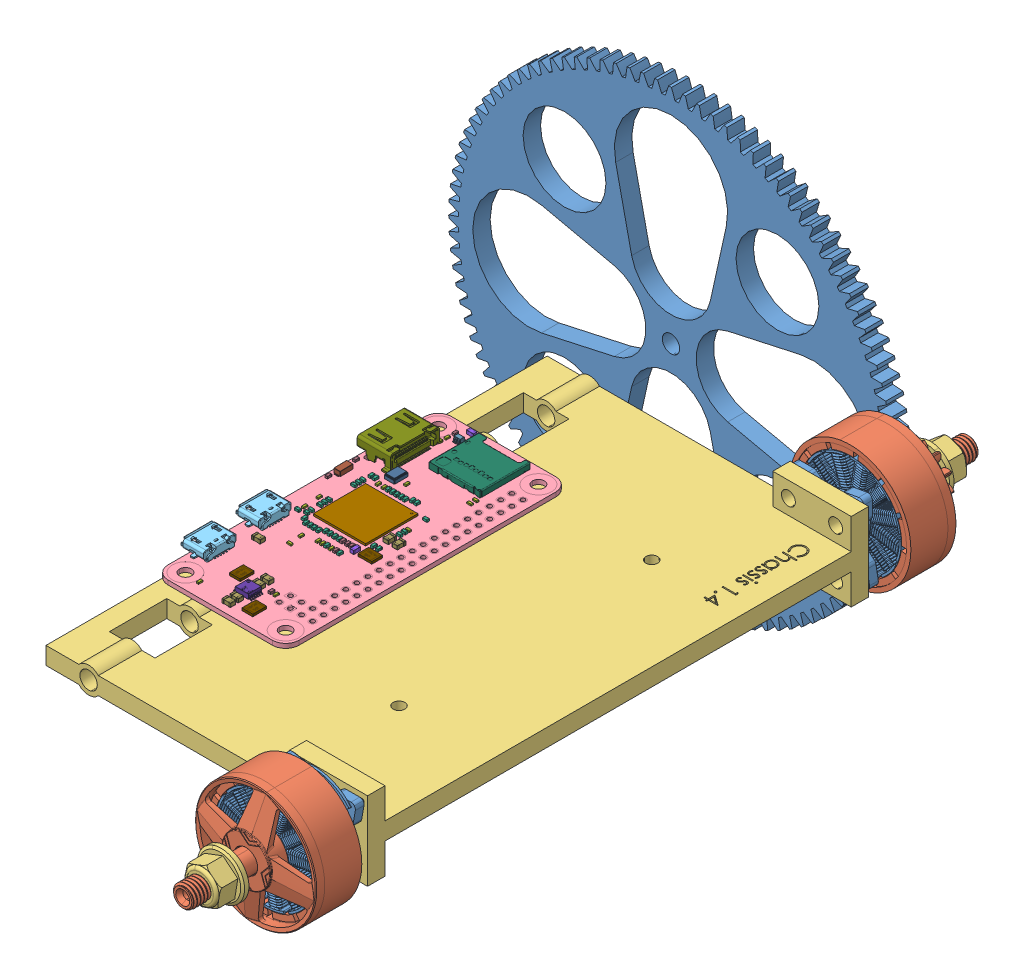
SolidWorks assembly dualwheel-drone, configuration Default. Lengths in mm.
Overall size (145.46 134.3 180.41).
93 component instances, 21 part files, 20 mates.
Components (placement in the parent):
- 100 spur gear 1 mod-1: 100 spur gear 1 mod [Metric - Spur gear 1M 100T 20PA 4FW ---S100N75H50L4N] at (0 0 -17) x (0 0 1) z (-0.401006 0.916076 0) size (4 101.97 101.97)
- spur gear_am-1: spur gear_am [Metric - Spur gear 1M 10T 20PA 4FW ---S10N75H50L5N] at (55 0 -17) x (0 0 1) z (-0.452539 -0.891745 0) size (4 11.48 12)
- chassis-full-1: chassis-full [Default] at (64 0 5.64) x (0 0 1) z (-1 0 0) size (115 18 73.78)
- RapberryPiZero.STEP-1: RapberryPiZero.STEP [Default] at (18.2777 -17.0965 114.3964) x (0 0 1) z (-1 0 0) size (65 4.45 31.23)
  - Raspberry_pizero_PCB.STEP-1: Raspberry_pizero_PCB.STEP [Default] at (-51.2564 20.0966 13.0542) size (65 1 30)
  - Micro USB_input_female (short)-SMT.STEP-1: Micro USB_input_female (short)-SMT.STEP [Default] at (-42.3564 22.3216 26.5042) size (7.98 2.94 5.43)
  - Micro USB_input_female (short)-SMT.STEP-2: Micro USB_input_female (short)-SMT.STEP [Default] at (-29.7564 22.3216 26.5042) size (7.98 2.94 5.43)
  - 0204 - Capacitor.STEP-1: 0204 - Capacitor.STEP [Default] at (-62.4121 21.3466 11.2398) size (1 0.5 0.6)
  - 0204 - Capacitor.STEP-2: 0204 - Capacitor.STEP [Default] at (-62.4121 21.3466 12.2528) size (1 0.5 0.6)
  - 0204 - Capacitor.STEP-3: 0204 - Capacitor.STEP [Default] at (-61.8122 21.3466 13.3136) size (1 0.5 0.6)
  - 0204 - Capacitor.STEP-4: 0204 - Capacitor.STEP [Default] at (-61.8122 21.3466 14.2646) size (1 0.5 0.6)
  - 0204 - Capacitor.STEP-5: 0204 - Capacitor.STEP [Default] at (-61.8122 21.3466 15.241) size (1 0.5 0.6)
  - 0204 - Capacitor.STEP-6: 0204 - Capacitor.STEP [Default] at (-61.8122 21.3466 16.2144) size (1 0.5 0.6)
  - 0204 - Capacitor.STEP-7: 0204 - Capacitor.STEP [Default] at (-61.8122 21.3466 17.2416) size (1 0.5 0.6)
  - 0204 - Capacitor.STEP-8: 0204 - Capacitor.STEP [Default] at (-62.5919 21.3466 20.9695) size (1 0.5 0.6)
  - 0204 - Capacitor.STEP-9: 0204 - Capacitor.STEP [Default] at (-62.5919 21.3466 21.919) size (1 0.5 0.6)
  - 0204 - Capacitor.STEP-10: 0204 - Capacitor.STEP [Default] at (-60.4584 21.3466 22.3712) x (0 0 1) z (-1 0 0) size (1 0.5 0.6)
  - 0204 - Capacitor.STEP-11: 0204 - Capacitor.STEP [Default] at (-60.0807 21.3466 22.3712) x (0 0 -1) z (1 0 0) size (1 0.5 0.6)
  - 0204 - Capacitor.STEP-12: 0204 - Capacitor.STEP [Default] at (-59.0466 21.3466 22.3712) x (0 0 -1) z (1 0 0) size (1 0.5 0.6)
  - 0204 - Capacitor.STEP-13: 0204 - Capacitor.STEP [Default] at (-52.6496 21.3466 22.316) x (0 0 1) z (-1 0 0) size (1 0.5 0.6)
  - 0204 - Capacitor.STEP-14: 0204 - Capacitor.STEP [Default] at (-52.25 21.3466 22.316) x (0 0 -1) z (1 0 0) size (1 0.5 0.6)
  - 0204 - Capacitor.STEP-15: 0204 - Capacitor.STEP [Default] at (-51.2398 21.3466 22.316) x (0 0 -1) z (1 0 0) size (1 0.5 0.6)
  - 0204 - Capacitor.STEP-16: 0204 - Capacitor.STEP [Default] at (-49.1841 21.3466 22.316) x (0 0 -1) z (1 0 0) size (1 0.5 0.6)
  - 0204 - Capacitor.STEP-17: 0204 - Capacitor.STEP [Default] at (-48.1448 21.3466 22.316) x (0 0 -1) z (1 0 0) size (1 0.5 0.6)
  - 0204 - Capacitor.STEP-18: 0204 - Capacitor.STEP [Default] at (-46.475 21.3466 21.113) size (1 0.5 0.6)
  - 0204 - Capacitor.STEP-19: 0204 - Capacitor.STEP [Default] at (-45.7322 21.3466 20.0663) size (1 0.5 0.6)
  - 0204 - Capacitor.STEP-20: 0204 - Capacitor.STEP [Default] at (-45.7322 21.3466 19.0675) size (1 0.5 0.6)
  - 0204 - Capacitor.STEP-21: 0204 - Capacitor.STEP [Default] at (-45.7322 21.3466 18.1249) size (1 0.5 0.6)
  - 0204 - Capacitor.STEP-22: 0204 - Capacitor.STEP [Default] at (-45.7322 21.3466 17.1095) size (1 0.5 0.6)
  - 0204 - Capacitor.STEP-23: 0204 - Capacitor.STEP [Default] at (-46.3457 21.3466 16.1412) size (1 0.5 0.6)
  - 0204 - Capacitor.STEP-24: 0204 - Capacitor.STEP [Default] at (-46.3457 21.3466 15.1229) size (1 0.5 0.6)
  - 0204 - Capacitor.STEP-25: 0204 - Capacitor.STEP [Default] at (-46.3457 21.3466 14.0197) size (1 0.5 0.6)
  - 0204 - Capacitor.STEP-26: 0204 - Capacitor.STEP [Default] at (-46.3457 21.3466 12.9589) size (1 0.5 0.6)
  - 0204 - Capacitor.STEP-27: 0204 - Capacitor.STEP [Default] at (-43.6156 21.3466 13.1418) size (1 0.5 0.6)
  - 0204 - Capacitor.STEP-28: 0204 - Capacitor.STEP [Default] at (-43.6156 21.3466 10.1424) size (1 0.5 0.6)
  - 0204 - Capacitor.STEP-29: 0204 - Capacitor.STEP [Default] at (-48.9117 21.3466 7.6917) size (1 0.5 0.6)
  - 0204 - Capacitor.STEP-30: 0204 - Capacitor.STEP [Default] at (-55.4926 21.3466 7.2526) x (0 0 -1) z (1 0 0) size (1 0.5 0.6)
  - 0204 - Capacitor.STEP-31: 0204 - Capacitor.STEP [Default] at (-53.7932 21.3466 7.2526) x (0 0 1) z (-1 0 0) size (1 0.5 0.6)
  - 0204 - Capacitor.STEP-32: 0204 - Capacitor.STEP [Default] at (-59.8477 21.3466 7.2526) x (0 0 1) z (-1 0 0) size (1 0.5 0.6)
  - 0204- Resistor.STEP-1: 0204- Resistor.STEP [Default] at (-43.6109 21.4522 15.4193) x (-1 0 0) z (0 -1 0) size (0.99 0.51 0.36)
  - 0204- Resistor.STEP-2: 0204- Resistor.STEP [Default] at (-43.6109 21.4522 14.4127) x (-1 0 0) z (0 -1 0) size (0.99 0.51 0.36)
  - 0204- Resistor.STEP-3: 0204- Resistor.STEP [Default] at (-43.6109 21.4522 12.4047) x (-1 0 0) z (0 -1 0) size (0.99 0.51 0.36)
  - 0204- Resistor.STEP-4: 0204- Resistor.STEP [Default] at (-42.6936 21.4522 18.4076) x (-1 0 0) z (0 -1 0) size (0.99 0.51 0.36)
  - 0204- Resistor.STEP-5: 0204- Resistor.STEP [Default] at (-39.831 21.4522 18.1462) x (0 0 1) z (0 -1 0) size (0.99 0.51 0.36)
  - 0204- Resistor.STEP-6: 0204- Resistor.STEP [Default] at (-61.8169 21.4522 19.8533) x (-1 0 0) z (0 -1 0) size (0.99 0.51 0.36)
  - 0204- Resistor.STEP-7: 0204- Resistor.STEP [Default] at (-61.8169 21.4522 18.5178) x (-1 0 0) z (0 -1 0) size (0.99 0.51 0.36)
  - 0204- Resistor.STEP-8: 0204- Resistor.STEP [Default] at (-79.148 21.4522 17.7279) x (-1 0 0) z (0 -1 0) size (0.99 0.51 0.36)
  - 0204- Resistor.STEP-9: 0204- Resistor.STEP [Default] at (-56.0985 21.4522 7.2479) x (0 0 -1) z (0 -1 0) size (0.99 0.51 0.36)
  - 0204- Resistor.STEP-10: 0204- Resistor.STEP [Default] at (-28.0827 21.4522 9.5819) x (-1 0 0) z (0 -1 0) size (0.99 0.51 0.36)
  - 0204- Resistor.STEP-11: 0204- Resistor.STEP [Default] at (-21.8613 21.4522 20.9026) x (-1 0 0) z (0 -1 0) size (0.99 0.51 0.36)
  - CAP-0306.STEP-1: CAP-0306.STEP [Default] at (-45.8903 21.4966 8.7634) size (1.6 0.8 0.9)
  - CAP-0306.STEP-2: CAP-0306.STEP [Default] at (-82.0031 21.4966 19.0464) x (0 0 1) z (-1 0 0) size (1.6 0.8 0.9)
  - Raspberry_pizero_BCM2835 with VC4.STEP-1: Raspberry_pizero_BCM2835 with VC4.STEP [Default] at (-54.1608 21.5466 15.1238) x (1 0 0) z (0 0 -1) size (12 0.65 12)
  - Crystal 3.4x2.4mm.STEP-1: Crystal 3.4x2.4mm.STEP [Default] at (-65.3089 21.0966 19.2633) size (3.2 1 2.4)
  - 0204- Resistor.STEP-12: 0204- Resistor.STEP [Default] at (-68.4329 21.4522 5.4384) x (0 0 1) z (0 -1 0) size (0.99 0.51 0.36)
  - 0204- Resistor.STEP-13: 0204- Resistor.STEP [Default] at (-69.7255 21.4522 5.4384) x (0 0 1) z (0 -1 0) size (0.99 0.51 0.36)
  - 0204- Resistor.STEP-14: 0204- Resistor.STEP [Default] at (-65.0626 21.4522 16.5355) x (1 0 0) z (0 -1 0) size (0.99 0.51 0.36)
  - 32,768 Khz Crystal.STEP-1: 32,768 Khz Crystal.STEP [Default] at (-60.5154 21.1428 26.5473) x (0.999848 -0.017452 0) z (0 0 1) size (3.4 1.03 1.5)
  - 0805- Capacitor.STEP-1: 0805- Capacitor.STEP [Default] at (-51.9496 21.9966 5.2384) x (1 0 0) z (0 -1 0) size (2 1.26 0.91)
  - 0805- Capacitor.STEP-2: 0805- Capacitor.STEP [Default] at (-51.9496 21.9966 7.3589) x (1 0 0) z (0 -1 0) size (2 1.26 0.91)
  - 0805- Capacitor.STEP-3: 0805- Capacitor.STEP [Default] at (-37.009 21.9966 22.5384) x (0 0 -1) z (0 -1 0) size (2 1.26 0.91)
  - 0805- Capacitor.STEP-4: 0805- Capacitor.STEP [Default] at (-29.8247 21.9966 13.3538) x (0 0 1) z (0 -1 0) size (2 1.26 0.91)
  - 0805- Capacitor.STEP-5: 0805- Capacitor.STEP [Default] at (-27.9052 21.9966 13.3538) x (0 0 -1) z (0 -1 0) size (2 1.26 0.91)
  - 0805- Capacitor.STEP-6: 0805- Capacitor.STEP [Default] at (-22.8003 21.9966 13.3538) x (0 0 -1) z (0 -1 0) size (2 1.26 0.91)
  - 0805- Capacitor.STEP-7: 0805- Capacitor.STEP [Default] at (-20.9924 21.9966 13.3538) x (0 0 -1) z (0 -1 0) size (2 1.26 0.91)
  - 0204- Resistor.STEP-15: 0204- Resistor.STEP [Default] at (-48.8769 21.4522 23.8207) x (1 0 0) z (0 -1 0) size (0.99 0.51 0.36)
  - 0204- Resistor.STEP-16: 0204- Resistor.STEP [Default] at (-52.4165 21.4522 24.0419) x (1 0 0) z (0 -1 0) size (0.99 0.51 0.36)
  - 0204 - Capacitor.STEP-33: 0204 - Capacitor.STEP [Default] at (-47.1199 21.3466 23.926) x (0 0 1) z (-1 0 0) size (1 0.5 0.6)
  - 0204 - Capacitor Brown.STEP-1: 0204 - Capacitor Brown.STEP [Default] at (-57.5817 21.3466 26.803) size (1 0.5 0.6)
  - 0204 - Capacitor Brown.STEP-2: 0204 - Capacitor Brown.STEP [Default] at (-64.0312 21.3466 26.8794) size (1 0.5 0.6)
  - 0204 - Capacitor Brown.STEP-3: 0204 - Capacitor Brown.STEP [Default] at (-46.3457 21.3466 12.214) size (1 0.5 0.6)
  - 0204 - Capacitor Brown.STEP-4: 0204 - Capacitor Brown.STEP [Default] at (-46.3457 21.3466 11.0963) size (1 0.5 0.6)
  - 0204 - Capacitor Brown.STEP-5: 0204 - Capacitor Brown.STEP [Default] at (-46.3457 21.3466 10.1566) size (1 0.5 0.6)
  - 0204 - Capacitor Brown.STEP-6: 0204 - Capacitor Brown.STEP [Default] at (-43.6156 21.3466 11.1151) size (1 0.5 0.6)
  - 0204 - Capacitor Brown.STEP-7: 0204 - Capacitor Brown.STEP [Default] at (-28.0874 21.3466 10.3236) size (1 0.5 0.6)
  - 0204 - Capacitor Brown.STEP-8: 0204 - Capacitor Brown.STEP [Default] at (-80.6197 21.3466 20.6997) size (1 0.5 0.6)
  - 0204- Resistor.STEP-17: 0204- Resistor.STEP [Default] at (-78.9105 21.4522 21.1554) x (1 0 0) z (0 -1 0) size (0.99 0.51 0.36)
  - 6-Pin SOT.STEP-1: 6-Pin SOT.STEP [Default] at (-79.714 21.0966 19.2138) x (0 0 1) z (0 1 0) size (1.5 1.84 0.95)
  - micro sd molex.STEP-1: micro sd molex.STEP [Default] at (-74.7768 21.6766 -33.0961) x (0 0 1) z (0 1 0) size (11.95 11.4 1.45)
  - hdmi type C.STEP-1: hdmi type C.STEP [Default] at (-71.3564 22.9466 28.6542) size (12.9 4.05 7.7)
  - Voltage Regulator 3x3mm 12-Pin.STEP-1: Voltage Regulator 3x3mm 12-Pin.STEP [Default] at (-23.6842 21.0966 12.6105) x (1 0 0) z (0 1 0) size (3 4.1 1.2)
  - 1210 inductor.STEP-1: 1210 inductor.STEP [Default] at (-46.4963 21.0916 6.3909) x (0 0 1) z (0 1 0) size (3.26 2.79 0.75)
  - 1210 inductor.STEP-2: 1210 inductor.STEP [Default] at (-22.7405 21.0916 9.2394) x (1 0 0) z (0 1 0) size (3.26 2.79 0.75)
  - 1210 inductor.STEP-3: 1210 inductor.STEP [Default] at (-28.2854 21.0916 17.6682) x (1 0 0) z (0 1 0) size (3.26 2.79 0.75)
  - 0204 - Capacitor.STEP-34: 0204 - Capacitor.STEP [Default] at (-48.9117 21.3466 6.5273) size (1 0.5 0.6)
- DYS Samguk Wei.STEP-1: DYS Samguk Wei.STEP [Default] at (54.2888 -0.2748 5.64) x (0.766044 -0.642788 0) z (0.642788 0.766044 0) size (39.17 32.71 39.17)
  - DYS Samguk Wei_Stator.STEP-1: DYS Samguk Wei_Stator.STEP [Default] at origin size (24 13.71 24)
  - DYS Samguk Wei_Rotor.STEP-1: DYS Samguk Wei_Rotor.STEP [Default] x (-0.7659 0 0.64296) z (-0.64296 0 -0.7659) size (27.8 32.7 27.8)
  - Ecrou_bleu.STEP-1: Ecrou_bleu.STEP [Default] at (0 22.9 0) x (0.330882 0 -0.943672) z (0.943672 0 0.330882) size (10.8 5.85 10.8)
- DYS Samguk Wei.STEP-2: DYS Samguk Wei.STEP [Default] at (54.2888 0.2748 120.64) x (0.766044 0.642788 0) z (0.642788 -0.766044 0) size (39.17 32.71 39.17)
  - DYS Samguk Wei_Stator.STEP-1: DYS Samguk Wei_Stator.STEP [Default] at origin size (24 13.71 24)
  - DYS Samguk Wei_Rotor.STEP-1: DYS Samguk Wei_Rotor.STEP [Default] x (-0.7659 0 0.64296) z (-0.64296 0 -0.7659) size (27.8 32.7 27.8)
  - Ecrou_bleu.STEP-1: Ecrou_bleu.STEP [Default] at (0 22.9 0) x (0.330882 0 -0.943672) z (0.943672 0 0.330882) size (10.8 5.85 10.8)
Mates (geometry in assembly coordinates):
- Concentric3: concentric: cylinder of 100 spur gear 1 mod-1 through (0 0 33.0001) axis (0 0 -1) radius 2
- Concentric4: concentric: cylinder of spur gear_am-1 through (55 0 33.0001) axis (0 0 -1) radius 2.5
- Distance4: distance = 13 mm: plane of assembly through (0 0 0) normal (0 0 1); plane of spur gear_am-7 through (0 0 -13) normal (0 0 1)
- Distance3: distance = 13 mm aligned: plane of spur gear_am-1 through (55 0 -13) normal (0 0 1)
- GearMate3: gear = 30 : 5 mm: cylinder of spur gear_am-1 through (55 0 33.0001) axis (0 0 -1) radius 2.5; cylinder of 100 spur gear 1 mod-1 through (0 0 33.0001) axis (0 0 -1) radius 2
- Concentric5: concentric aligned: cylinder of 100 spur gear 1 mod-1 through (0 0 33.0001) axis (0 0 -1) radius 2; cylinder of chassis-full-1 through (0 0 120.64) axis (0 0 -1) radius 2
- Perpendicular2: perpendicular: plane of chassis-full-1 through (64 2 5.64) normal (0 0 -1)
- Perpendicular3: perpendicular: plane of chassis-full-1 through (64 2 5.64) normal (1 0 0)
- Parallel7: parallel anti-aligned: plane of 100 spur gear 1 mod-1 through (0 0 -13) normal (0 0 1); plane of chassis-full-1 through (64 2 5.64) normal (0 0 -1)
- Concentric11: concentric anti-aligned: circle of chassis-full-1; circle of RapberryPiZero.STEP-1/Raspberry_pizero_PCB.STEP-1
- Concentric12: concentric anti-aligned: circle of chassis-full-1; cylinder of RapberryPiZero.STEP-1/Raspberry_pizero_PCB.STEP-1 through (-6.2765 4.0001 34.14) axis (0 -1 0) radius 1.375
- Concentric13: concentric aligned: circle of chassis-full-1; circle of RapberryPiZero.STEP-1/Raspberry_pizero_PCB.STEP-1
- Concentric14: concentric anti-aligned: circle of chassis-full-1; cylinder of RapberryPiZero.STEP-1/Raspberry_pizero_PCB.STEP-1 through (-6.2765 4.0001 92.14) axis (0 -1 0) radius 1.375
- LimitDistance4: limit distance = 1.0001 mm anti-aligned: plane of RapberryPiZero.STEP-1/Raspberry_pizero_PCB.STEP-1 through (17.2235 3.0001 33.64) normal (0 -1 0); plane of chassis-full-1 through (64 2 5.64) normal (0 1 0)
- Coincident3: coincident anti-aligned: plane of chassis-full-1 through (64 2 5.64) normal (0 0 -1); plane of DYS Samguk Wei.STEP-1/DYS Samguk Wei_Rotor.STEP-1 through (54.2888 -0.2748 5.64) normal (0 0 1)
- Concentric17: concentric anti-aligned: cylinder of chassis-full-1 through (60.4172 -5.4172 9.64) axis (0 0 -1) radius 1.6; circle of DYS Samguk Wei.STEP-1/DYS Samguk Wei_Stator.STEP-1
- Parallel8: parallel aligned: plane of chassis-full-1 through (64 2 5.64) normal (1 0 0); plane of DYS Samguk Wei.STEP-1/DYS Samguk Wei_Stator.STEP-1 through (62.3595 8.1516 3.14) normal (1 0 0)
- Coincident4: coincident anti-aligned: plane of chassis-full-1 through (64 2 120.64) normal (0 0 1); plane of DYS Samguk Wei.STEP-2/DYS Samguk Wei_Rotor.STEP-1 through (54.2888 0.2748 120.64) normal (0 0 -1)
- Concentric19: concentric anti-aligned: circle of DYS Samguk Wei.STEP-2/DYS Samguk Wei_Stator.STEP-1; cylinder of chassis-full-1 through (60.4172 5.4172 116.64) axis (0 0 1) radius 1.6
- Parallel9: parallel aligned: plane of chassis-full-1 through (64 2 5.64) normal (1 0 0); plane of DYS Samguk Wei.STEP-2/DYS Samguk Wei_Stator.STEP-1 through (62.3595 -8.1516 123.14) normal (1 0 0)
